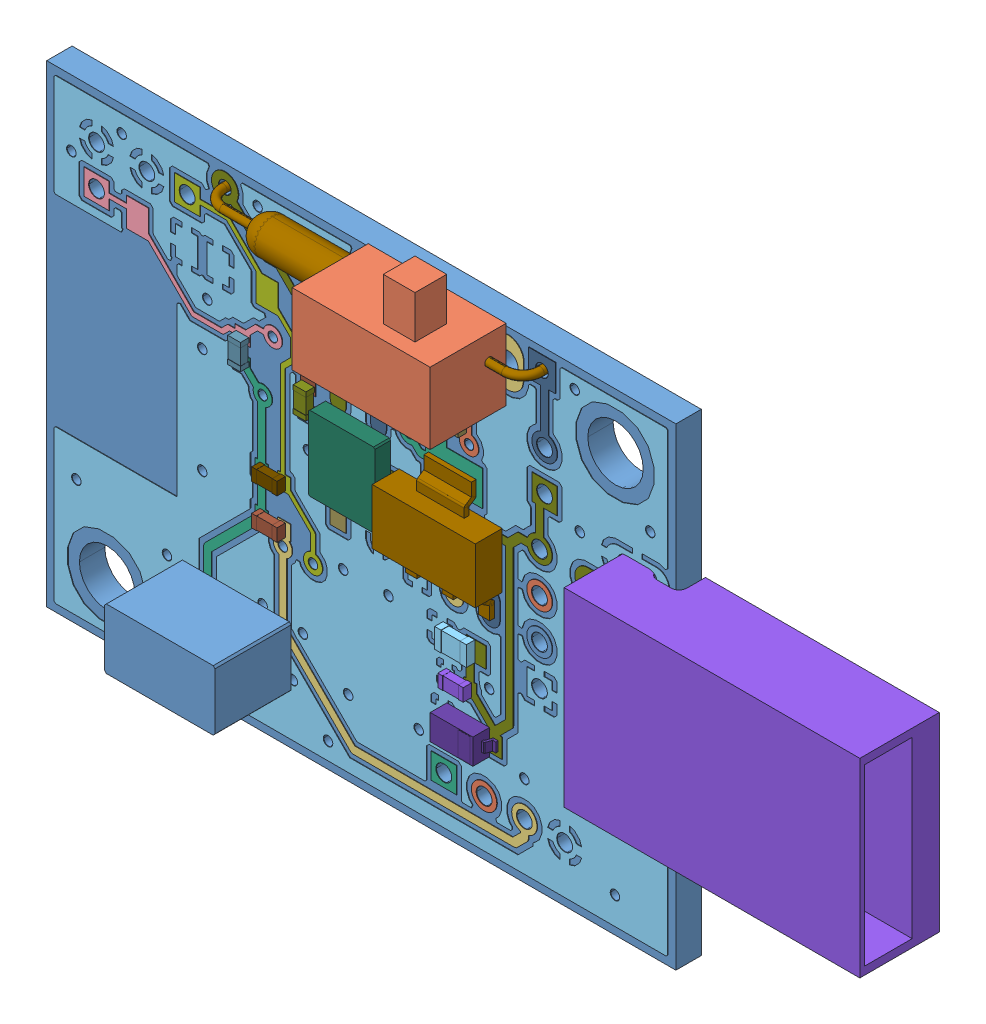
SolidWorks assembly ESP_Sensors_V1.0_Panel, configuration Défaut. Lengths in mm.
Overall size (54.84 32.82 9.37).
104 component instances, 50 part files, 0 mates.
Components (placement in the parent):
- ESP_Sensors_V1.0_Panel.stp-1: ESP_Sensors_V1.0_Panel.stp [Défaut] at origin size (54.84 32.82 14.47)
  - Board_assembly.stp-1: Board_assembly.stp [Défaut] at origin size (39.69 29.84 1.6)
    - Board.stp-1: Board.stp [Défaut] at origin size (39.69 29.84 1.6)
  - PadsAndTracks_assembly.stp-1: PadsAndTracks_assembly.stp [Défaut] at origin size (38.8 28.94 1.67)
    - Copper_2_assembly.stp-1: Copper_2_assembly.stp [Défaut] at origin size (16.2 20.97 1.67)
      - Copper_2.stp-1: Copper_2.stp [Défaut] at origin size (16.2 20.97 1.67)
    - Copper_3_assembly.stp-1: Copper_3_assembly.stp [Défaut] at origin size (16.74 10.58 1.67)
      - Copper_3.stp-1: Copper_3.stp [Défaut] at origin size (16.74 10.58 1.67)
    - Copper_RST_assembly.stp-1: Copper_RST_assembly.stp [Défaut] at origin size (13.15 4.77 1.67)
      - Copper_RST.stp-1: Copper_RST.stp [Défaut] at origin size (13.15 4.77 1.67)
    - Copper_GND_assembly.stp-1: Copper_GND_assembly.stp [Défaut] at origin size (38.8 28.85 1.67)
      - Copper_GND.stp-1: Copper_GND.stp [Défaut] at origin size (38.8 28.85 1.67)
    - Copper_+3V_assembly.stp-1: Copper_+3V_assembly.stp [Défaut] at origin size (19.37 24.63 1.67)
      - Copper_+3V.stp-1: Copper_+3V.stp [Défaut] at origin size (19.37 24.63 1.67)
    - Copper_GPIO0_assembly.stp-1: Copper_GPIO0_assembly.stp [Défaut] at origin size (9.43 20.03 1.67)
      - Copper_GPIO0.stp-1: Copper_GPIO0.stp [Défaut] at origin size (9.43 20.03 1.67)
    - Copper_Sig$7_assembly.stp-1: Copper_Sig$7_assembly.stp [Défaut] at origin size (2.55 4.88 0.03)
      - Copper_Sig$7.stp-1: Copper_Sig$7.stp [Défaut] at origin size (2.55 4.88 0.03)
    - Copper_Sig$8_assembly.stp-1: Copper_Sig$8_assembly.stp [Défaut] at origin size (1.69 4.71 0.03)
      - Copper_Sig$8.stp-1: Copper_Sig$8.stp [Défaut] at origin size (1.69 4.71 0.03)
    - Copper_L2_assembly.stp-1: Copper_L2_assembly.stp [Défaut] at origin size (11.78 16.48 1.67)
      - Copper_L2.stp-1: Copper_L2.stp [Défaut] at origin size (11.78 16.48 1.67)
    - Copper_in+_assembly.stp-1: Copper_in+_assembly.stp [Défaut] at origin size (1.5 5.27 1.67)
      - Copper_in+.stp-1: Copper_in+.stp [Défaut] at origin size (1.5 5.27 1.67)
    - Copper_Sig$11_assembly.stp-1: Copper_Sig$11_assembly.stp [Défaut] at origin size (2.89 5.9 0.03)
      - Copper_Sig$11.stp-1: Copper_Sig$11.stp [Défaut] at origin size (2.89 5.9 0.03)
    - Copper_Sig$12_assembly.stp-1: Copper_Sig$12_assembly.stp [Défaut] at origin size (4.96 6.51 1.67)
      - Copper_Sig$12.stp-1: Copper_Sig$12.stp [Défaut] at origin size (4.96 6.51 1.67)
    - Copper_Sig$13_assembly.stp-1: Copper_Sig$13_assembly.stp [Défaut] at origin size (4.21 6.51 1.67)
      - Copper_Sig$13.stp-1: Copper_Sig$13.stp [Défaut] at origin size (4.21 6.51 1.67)
    - Copper_Sig$14_assembly.stp-1: Copper_Sig$14_assembly.stp [Défaut] at origin size (7.25 5.15 1.67)
      - Copper_Sig$14.stp-1: Copper_Sig$14.stp [Défaut] at origin size (7.25 5.15 1.67)
    - Copper_VDD_assembly.stp-1: Copper_VDD_assembly.stp [Défaut] at origin size (26.42 23.37 1.67)
      - Copper_VDD.stp-1: Copper_VDD.stp [Défaut] at origin size (26.42 23.37 1.67)
    - Copper_Sig$16_assembly.stp-1: Copper_Sig$16_assembly.stp [Défaut] at origin size (1.21 4.34 0.03)
      - Copper_Sig$16.stp-1: Copper_Sig$16.stp [Défaut] at origin size (1.21 4.34 0.03)
    - Copper_Sig$17_assembly.stp-1: Copper_Sig$17_assembly.stp [Défaut] at origin size (5.66 6.54 0.03)
      - Copper_Sig$17.stp-1: Copper_Sig$17.stp [Défaut] at origin size (5.66 6.54 0.03)
    - Copper_D_+_assembly.stp-1: Copper_D_+_assembly.stp [Défaut] at origin size (6.53 1.9 1.67)
      - Copper_D_+.stp-1: Copper_D_+.stp [Défaut] at origin size (6.53 1.9 1.67)
    - Copper_D_-_assembly.stp-1: Copper_D_-_assembly.stp [Défaut] at origin size (6.53 1.9 1.67)
      - Copper_D_-.stp-1: Copper_D_-.stp [Défaut] at origin size (6.53 1.9 1.67)
    - Copper__assembly.stp-1: Copper__assembly.stp [Défaut] at origin size (11.89 16.5 1.67)
      - Copper_.stp-1: Copper_.stp [Défaut] at origin size (11.89 16.5 1.67)
  - J1_assembly.stp-1: J1_assembly.stp [Défaut] at origin size (2.54 10.16 12) (hidden)
    - J1.stp-1: J1.stp [Défaut] at origin size (2.54 10.16 12)
  - X2_assembly.stp-1: X2_assembly.stp [Défaut] at origin size (24 16 2.8)
    - X2.stp-1: X2.stp [Défaut] at origin size (24 16 2.8)
  - J2_assembly.stp-1: J2_assembly.stp [Défaut] at origin size (10.16 2.54 12) (hidden)
    - J2.stp-1: J2.stp [Défaut] at origin size (10.16 2.54 12)
  - C3_assembly.stp-1: C3_assembly.stp [Défaut] at origin size (2 1.25 0.53)
    - C3.stp-1: C3.stp [Défaut] at origin size (2 1.25 0.53)
  - C4_assembly.stp-1: C4_assembly.stp [Défaut] at origin size (1.6 0.8 0.53)
    - C4.stp-1: C4.stp [Défaut] at origin size (1.6 0.8 0.53)
  - C5_assembly.stp-1: C5_assembly.stp [Défaut] at origin size (0.8 1.6 0.53)
    - C5.stp-1: C5.stp [Défaut] at origin size (0.8 1.6 0.53)
  - C6_assembly.stp-1: C6_assembly.stp [Défaut] at origin size (1.6 0.8 0.53)
    - C6.stp-1: C6.stp [Défaut] at origin size (1.6 0.8 0.53)
  - IC1_assembly.stp-1: IC1_assembly.stp [Défaut] at origin size (6.5 7 1.8)
    - IC1.stp-1: IC1.stp [Défaut] at origin size (6.5 7 1.8)
  - R1_assembly.stp-1: R1_assembly.stp [Défaut] at origin size (0.8 1.6 0.53)
    - R1.stp-1: R1.stp [Défaut] at origin size (0.8 1.6 0.53)
  - R2_assembly.stp-1: R2_assembly.stp [Défaut] at origin size (1.6 0.8 0.53)
    - R2.stp-1: R2.stp [Défaut] at origin size (1.6 0.8 0.53)
  - R3_assembly.stp-1: R3_assembly.stp [Défaut] at origin size (1.6 0.8 0.53)
    - R3.stp-1: R3.stp [Défaut] at origin size (1.6 0.8 0.53)
  - R5_assembly.stp-1: R5_assembly.stp [Défaut] at origin size (1.6 0.8 0.53)
    - R5.stp-1: R5.stp [Défaut] at origin size (1.6 0.8 0.53)
  - R6_assembly.stp-1: R6_assembly.stp [Défaut] at origin size (0.8 1.6 0.53)
    - R6.stp-1: R6.stp [Défaut] at origin size (0.8 1.6 0.53)
  - RE1_assembly.stp-1: RE1_assembly.stp [Défaut] at origin size (4.2 4.7 1)
    - RE1.stp-1: RE1.stp [Défaut] at origin size (4.2 4.7 1)
  - R4_assembly.stp-1: R4_assembly.stp [Défaut] at origin size (0.8 1.6 0.53)
    - R4.stp-1: R4.stp [Défaut] at origin size (0.8 1.6 0.53)
  - D1_assembly.stp-1: D1_assembly.stp [Défaut] at origin size (3.68 1.6 1.11)
    - D1.stp-1: D1.stp [Défaut] at origin size (3.68 1.6 1.11)
  - R7_assembly.stp-1: R7_assembly.stp [Défaut] at origin size (1.6 0.8 0.53)
    - R7.stp-1: R7.stp [Défaut] at origin size (1.6 0.8 0.53)
  - J3_assembly.stp-1: J3_assembly.stp [Défaut] at origin size (6.96 3.8 4.8)
    - J3.stp-1: J3.stp [Défaut] at origin size (6.96 3.8 4.8)
  - S4_assembly.stp-1: S4_assembly.stp [Défaut] at origin size (8.7 7.2 4.8)
    - S4.stp-1: S4.stp [Défaut] at origin size (8.7 7.2 4.8)
  - R8_assembly.stp-1: R8_assembly.stp [Défaut] at origin size (1.6 0.8 0.53)
    - R8.stp-1: R8.stp [Défaut] at origin size (1.6 0.8 0.53)
  - R9_assembly.stp-1: R9_assembly.stp [Défaut] at origin size (1.6 0.8 0.53)
    - R9.stp-1: R9.stp [Défaut] at origin size (1.6 0.8 0.53)
  - J4_assembly.stp-1: J4_assembly.stp [Défaut] at origin size (2.39 1.6 0.2)
    - J4.stp-1: J4.stp [Défaut] at origin size (2.39 1.6 0.2)
  - J5_assembly.stp-1: J5_assembly.stp [Défaut] at origin size (2.54 5.08 12) (hidden)
    - J5.stp-1: J5.stp [Défaut] at origin size (2.54 5.08 12)
  - C2_assembly.stp-1: C2_assembly.stp [Défaut] at origin size (5.08 2.54 12) (hidden)
    - C2.stp-1: C2.stp [Défaut] at origin size (5.08 2.54 12)
  - R10_assembly.stp-1: R10_assembly.stp [Défaut] at origin size (0.8 1.6 0.53)
    - R10.stp-1: R10.stp [Défaut] at origin size (0.8 1.6 0.53)
  - D2_assembly.stp-1: D2_assembly.stp [Défaut] at origin size (3.5 2.8 2.1)
    - D2.stp-1: D2.stp [Défaut] at origin size (3.5 2.8 2.1)
  - J8_assembly.stp-1: J8_assembly.stp [Défaut] at origin size (2.54 5.08 12) (hidden)
    - J8.stp-1: J8.stp [Défaut] at origin size (2.54 5.08 12)
  - J7_assembly.stp-1: J7_assembly.stp [Défaut] at origin size (20.08 12 6.51)
    - J7_step1_assembly.stp-1: J7_step1_assembly.stp [Défaut] at (36.185 14.9225 -1.5043) size (20.08 12 6.51)
      - USB Connector Typ A ASSEMBLY.stp-1: USB Connector Typ A ASSEMBLY.stp [Défaut] at origin size (20.08 12 6.51)
        - USB Connector Typ A Fillet002.stp-1: USB Connector Typ A Fillet002.stp [Défaut] at origin size (20.08 12 6.51)
  - X3_assembly.stp-1: X3_assembly.stp [Défaut] at origin size (20.5 2.2 4.3)
    - X3.stp-1: X3.stp [Défaut] at origin size (20.5 2.2 4.3)
